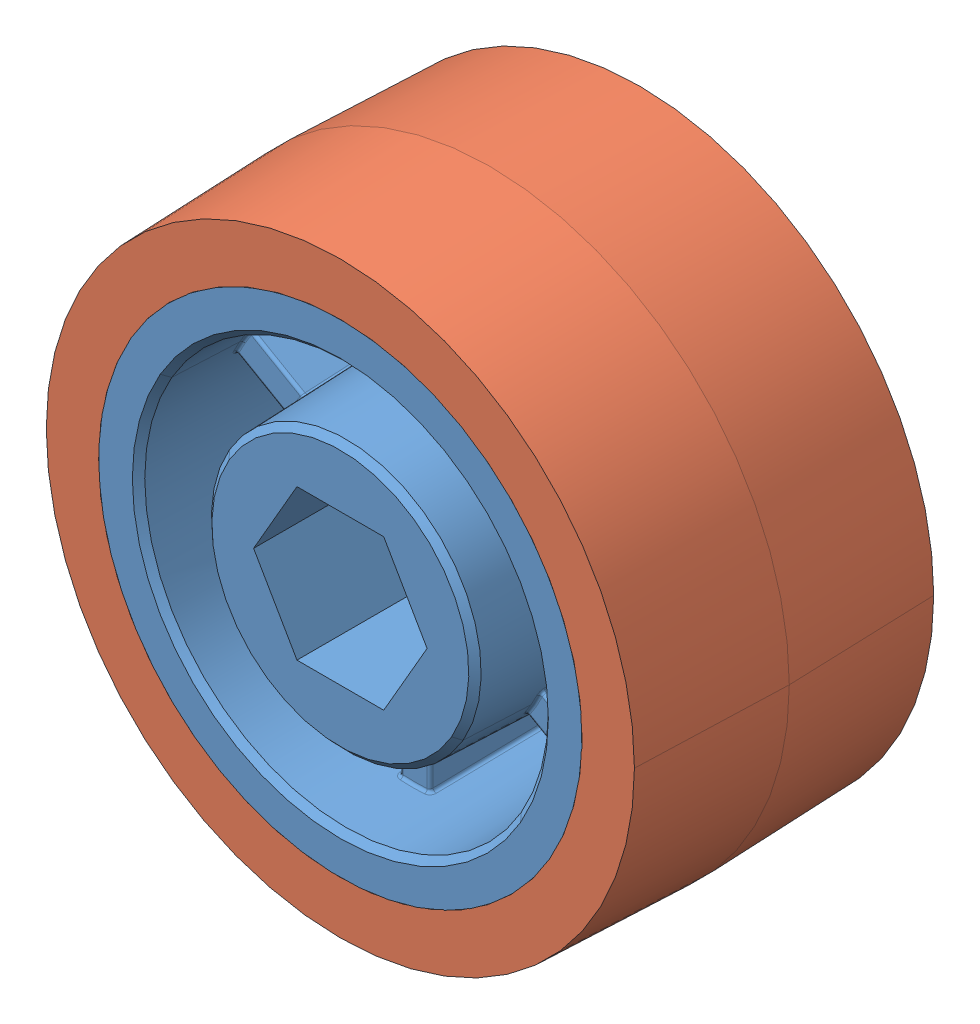
SolidWorks assembly am-3155 2IN 500Hex Stealth Wheel REV2.STEP, configuration Default. Lengths in mm.
Overall size (57.25 57.25 25.4).
2 component instances, 2 part files, 0 mates.
Components (placement in the parent):
- 2in Wheel Intergrated 0500 HEX Hub.STEP-1: 2in Wheel Intergrated 0500 HEX Hub.STEP [Default] at (20.955 20.955 -12.7) x (-0.866025 0.5 0) z (0 0 -1) size (41.91 41.91 25.4)
- 2in Tread.STEP-1: 2in Tread.STEP [Default] at (20.955 20.955 -12.7) x (0 0 -1) z (1 0 0) size (25.4 50.8 50.8)
